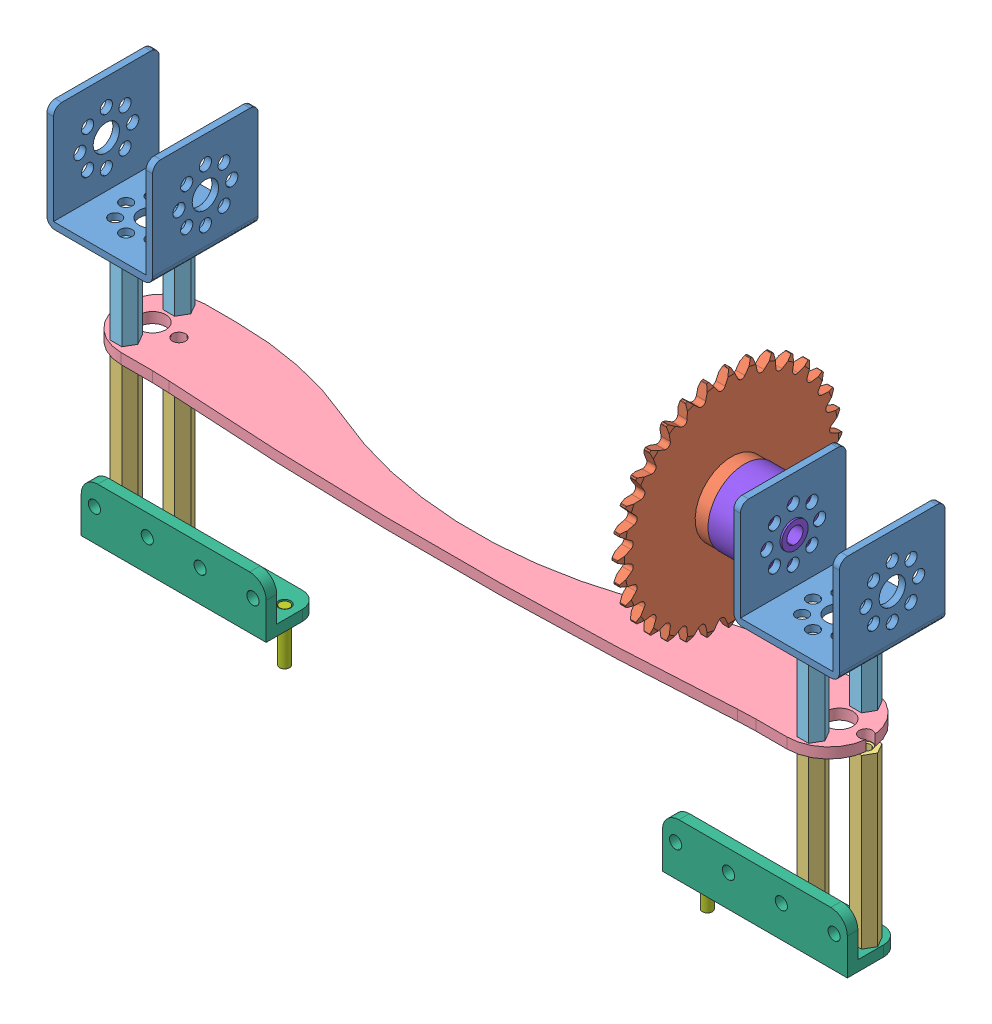
SolidWorks assembly Goal Latch, configuration Default. Lengths in mm.
Overall size (431.8 262.6 648.94).
16 component instances, 8 part files, 45 mates.
Components (placement in the parent):
- Tetrix Channel 32mm-1: Tetrix Channel 32mm [Default] at (-103.35 212.6 177.8) size (32 32 32)
- Tetrix Channel 32mm-2: Tetrix Channel 32mm [Default] at (104.65 212.6 177.8) size (32 32 32)
- Tetrix Sprocket 32T-1: Tetrix Sprocket 32T [Default] at (71.95 228.6 177.8) x (0 1 0) z (1 0 0) size (68 68 6.8)
- Tetrix Standoff 2in'-1: Tetrix Standoff 2in' [Default] at (-111.35 184.025 177.8) x (1 0 0) z (0 -1 0) size (7.16 6.2 50.8)
- Goal Latch Bar (Plasmacut)-1: Goal Latch Bar (Plasmacut) [Default] at (-100.175 187.2 177.8) x (1 0 0) z (0 -1 0) size (226.91 28.57 3.17)
- Tetrix Standoff 1in-1: Tetrix Standoff 1in [Default] at (-103.35 212.6 169.8) x (1 0 0) z (0 -1 0) size (7.16 6.2 25.4)
- Tetrix Standoff 1in-2: Tetrix Standoff 1in [Default] at (-103.35 212.6 185.8) x (1 0 0) z (0 -1 0) size (7.16 6.2 25.4)
- Tetrix Standoff 1in-3: Tetrix Standoff 1in [Default] at (104.65 212.6 169.8) x (1 0 0) z (0 -1 0) size (7.16 6.2 25.4)
- Tetrix Standoff 1in-4: Tetrix Standoff 1in [Default] at (104.65 212.6 185.8) x (1 0 0) z (0 -1 0) size (7.16 6.2 25.4)
- Tetrix Standoff 2in'-2: Tetrix Standoff 2in' [Default] at (-95.35 184.025 177.8) x (1 0 0) z (0 -1 0) size (7.16 6.2 50.8)
- Tetrix Standoff 2in'-3: Tetrix Standoff 2in' [Default] at (112.65 184.025 177.8) x (1 0 0) z (0 -1 0) size (7.16 6.2 50.8)
- Tetrix Standoff 2in'-4: Tetrix Standoff 2in' [Default] at (96.65 184.025 177.8) x (1 0 0) z (0 -1 0) size (7.16 6.2 50.8)
- Goal Latch Angle-1: Goal Latch Angle [Default] at (-39.35 130.025 187.4) x (0 0 -1) z (1 0 0) size (16 16 56)
- Goal Latch Angle-2: Goal Latch Angle [Default] at (136.65 130.025 187.4) x (0 0 -1) z (1 0 0) size (16 16 56)
- Part1^Goal Latch-2: Part1^Goal Latch [Default] at (-39.35 130.025 187.4) x (0 0 1) z (0 -1 0) size (3 131 15.7) (virtual)
- Tetrix Gear Spacer-1: Tetrix Gear Spacer [Default] at (82.3 228.6 177.8) x (0 0 1) z (-1 0 0) size (22.2 22.2 17.75)
Mates (geometry in assembly coordinates):
- Coincident3: coincident aligned: plane of Tetrix Channel 32mm-1 through (-119.35 212.6 161.8) normal (0 -1 0); plane of Tetrix Channel 32mm-2 through (88.65 212.6 161.8) normal (0 -1 0)
- Distance4: distance = 120.65 mm aligned: plane of Tetrix Channel 32mm-2 through (120.65 212.6 161.8) normal (1 0 0); plane of assembly through (0 0 0) normal (1 0 0)
- Concentric23: concentric aligned: cylinder of Tetrix Channel 32mm-1 through (-87.35 228.6 177.8) axis (1 0 0) radius 4; cylinder of Tetrix Channel 32mm-2 through (120.65 228.6 177.8) axis (1 0 0) radius 4
- Concentric24: concentric aligned: cylinder of Tetrix Channel 32mm-2 through (120.65 228.6 177.8) axis (1 0 0) radius 4; cylinder of Tetrix Sprocket 32T-1 through (69.15 228.6 177.8) axis (1 0 0) radius 4
- Distance7: distance = 177.8 mm: plane of assembly through (0 0 0) normal (0 0 1); axis of Tetrix Channel 32mm-1 through (-89.35 228.6 177.8) axis (1 0 0)
- Distance8: distance = 228.6 mm: axis of Tetrix Sprocket 32T-1 through (75.95 228.6 177.8) axis (-1 0 0); plane of assembly
- Concentric25: concentric aligned: cylinder of Tetrix Channel 32mm-2 through (120.65 228.6 185.8) axis (1 0 0) radius 1.85; cylinder of Tetrix Sprocket 32T-1 through (69.15 228.6 185.8) axis (1 0 0) radius 1.8
- Coincident11: coincident aligned: plane of Tetrix Standoff 1in-1 through (-103.35 212.6 169.8) normal (0 1 0); plane of Tetrix Standoff 1in-2 through (-103.35 212.6 185.8) normal (0 1 0)
- Coincident12: coincident aligned: plane of Tetrix Standoff 1in-2 through (-103.35 212.6 185.8) normal (0 1 0); plane of Tetrix Standoff 1in-4 through (104.65 212.6 185.8) normal (0 1 0)
- Coincident13: coincident aligned: plane of Tetrix Standoff 1in-3 through (104.65 212.6 169.8) normal (0 1 0); plane of Tetrix Standoff 1in-4 through (104.65 212.6 185.8) normal (0 1 0)
- Coincident14: coincident anti-aligned: plane of Tetrix Channel 32mm-2 through (88.65 212.6 161.8) normal (0 -1 0); plane of Tetrix Standoff 1in-3 through (104.65 212.6 169.8) normal (0 1 0)
- Concentric26: concentric aligned: cylinder of Tetrix Channel 32mm-2 through (104.65 214.6 185.8) axis (0 1 0) radius 1.85; cylinder of Tetrix Standoff 1in-4 through (104.65 187.2 185.8) axis (0 1 0) radius 1.5
- Concentric27: concentric aligned: cylinder of Tetrix Channel 32mm-2 through (104.65 214.6 169.8) axis (0 1 0) radius 1.85; cylinder of Tetrix Standoff 1in-3 through (104.65 187.2 169.8) axis (0 1 0) radius 1.5
- Concentric28: concentric aligned: cylinder of Tetrix Channel 32mm-1 through (-103.35 214.6 185.8) axis (0 1 0) radius 1.85; cylinder of Tetrix Standoff 1in-2 through (-103.35 187.2 185.8) axis (0 1 0) radius 1.5
- Concentric29: concentric aligned: cylinder of Tetrix Channel 32mm-1 through (-103.35 214.6 169.8) axis (0 1 0) radius 1.85; cylinder of Tetrix Standoff 1in-1 through (-103.35 187.2 169.8) axis (0 1 0) radius 1.5
- Parallel1: parallel aligned: plane of Tetrix Standoff 1in-1 through (-101.5602 212.6 172.9) normal (0 0 1); plane of Tetrix Standoff 1in-2 through (-101.5602 212.6 188.9) normal (0 0 1)
- Parallel2: parallel aligned: plane of Tetrix Channel 32mm-1 through (-103.35 212.6 193.8) normal (0 0 1); plane of Tetrix Standoff 1in-2 through (-101.5602 212.6 188.9) normal (0 0 1)
- Parallel3: parallel aligned: plane of Tetrix Standoff 1in-2 through (-101.5602 212.6 188.9) normal (0 0 1); plane of Tetrix Standoff 1in-4 through (106.4398 212.6 188.9) normal (0 0 1)
- Parallel4: parallel aligned: plane of Tetrix Standoff 1in-3 through (106.4398 212.6 172.9) normal (0 0 1); plane of Tetrix Standoff 1in-4 through (106.4398 212.6 188.9) normal (0 0 1)
- Coincident19: coincident anti-aligned: plane of Goal Latch Bar (Plasmacut)-1 through (-100.175 187.2 177.8) normal (0 1 0); plane of Tetrix Standoff 1in-4 through (104.65 187.2 185.8) normal (0 -1 0)
- Concentric30: concentric anti-aligned: cylinder of Goal Latch Bar (Plasmacut)-1 through (104.65 187.2 185.8) axis (0 -1 0) radius 1.9844; cylinder of Tetrix Standoff 1in-4 through (104.65 187.2 185.8) axis (0 1 0) radius 1.5
- Concentric31: concentric anti-aligned: cylinder of Goal Latch Bar (Plasmacut)-1 through (104.65 187.2 169.8) axis (0 -1 0) radius 1.9844; cylinder of Tetrix Standoff 1in-3 through (104.65 187.2 169.8) axis (0 1 0) radius 1.5
- Concentric33: concentric anti-aligned: cylinder of Goal Latch Bar (Plasmacut)-1 through (-103.35 187.2 185.8) axis (0 -1 0) radius 1.9844; cylinder of Tetrix Standoff 1in-2 through (-103.35 187.2 185.8) axis (0 1 0) radius 1.5
- Parallel6: parallel aligned: plane of Tetrix Channel 32mm-2 through (104.65 212.6 193.8) normal (0 0 1); plane of assembly through (0 0 0) normal (0 0 1)
- Coincident21: coincident aligned: plane of Tetrix Standoff 2in'-1 through (-111.35 184.025 177.8) normal (0 1 0); plane of Tetrix Standoff 2in'-2 through (-95.35 184.025 177.8) normal (0 1 0)
- Coincident22: coincident aligned: plane of Tetrix Standoff 2in'-3 through (112.65 184.025 177.8) normal (0 1 0); plane of Tetrix Standoff 2in'-4 through (96.65 184.025 177.8) normal (0 1 0)
- Coincident23: coincident aligned: plane of Tetrix Standoff 2in'-2 through (-95.35 184.025 177.8) normal (0 1 0); plane of Tetrix Standoff 2in'-4 through (96.65 184.025 177.8) normal (0 1 0)
- Coincident24: coincident anti-aligned: plane of Goal Latch Bar (Plasmacut)-1 through (-100.175 184.025 177.8) normal (0 -1 0); plane of Tetrix Standoff 2in'-2 through (-95.35 184.025 177.8) normal (0 1 0)
- Concentric34: concentric anti-aligned: cylinder of Goal Latch Bar (Plasmacut)-1 through (-95.35 187.2 177.8) axis (0 -1 0) radius 1.9844; cylinder of Tetrix Standoff 2in'-2 through (-95.35 133.225 177.8) axis (0 1 0) radius 1.5
- Concentric35: concentric anti-aligned: cylinder of Tetrix Standoff 2in'-1 through (-111.35 133.225 177.8) axis (0 1 0) radius 1.5; cylinder of Goal Latch Bar (Plasmacut)-1 through (-111.35 187.2 177.8) axis (0 -1 0) radius 1.9844
- Concentric36: concentric anti-aligned: cylinder of Goal Latch Bar (Plasmacut)-1 through (96.65 187.2 177.8) axis (0 -1 0) radius 1.9844; cylinder of Tetrix Standoff 2in'-4 through (96.65 133.225 177.8) axis (0 1 0) radius 1.5
- Concentric37: concentric anti-aligned: cylinder of Goal Latch Bar (Plasmacut)-1 through (112.65 187.2 177.8) axis (0 -1 0) radius 1.9844; cylinder of Tetrix Standoff 2in'-3 through (112.65 133.225 177.8) axis (0 1 0) radius 1.5
- Coincident26: coincident anti-aligned: plane of Tetrix Standoff 2in'-2 through (-95.35 133.225 177.8) normal (0 -1 0); plane of Goal Latch Angle-1 through (-39.35 133.225 171.4) normal (0 1 0)
- Coincident27: coincident aligned: plane of Goal Latch Angle-1 through (-39.35 133.225 171.4) normal (0 1 0); plane of Goal Latch Angle-2 through (136.65 133.225 171.4) normal (0 1 0)
- Concentric38: concentric anti-aligned: cylinder of Tetrix Standoff 2in'-1 through (-111.35 133.225 177.8) axis (0 1 0) radius 1.5; cylinder of Goal Latch Angle-1 through (-111.35 133.225 177.8) axis (0 -1 0) radius 1.85
- Concentric39: concentric anti-aligned: cylinder of Tetrix Standoff 2in'-2 through (-95.35 133.225 177.8) axis (0 1 0) radius 1.5; cylinder of Goal Latch Angle-1 through (-95.35 133.225 177.8) axis (0 -1 0) radius 1.85
- Concentric40: concentric anti-aligned: cylinder of Tetrix Standoff 2in'-3 through (112.65 133.225 177.8) axis (0 1 0) radius 1.5; cylinder of Goal Latch Angle-2 through (112.65 133.225 177.8) axis (0 -1 0) radius 1.85
- Concentric41: concentric anti-aligned: cylinder of Tetrix Standoff 2in'-4 through (96.65 133.225 177.8) axis (0 1 0) radius 1.5; cylinder of Goal Latch Angle-2 through (96.65 133.225 177.8) axis (0 -1 0) radius 1.85
- InPlace1: in place: plane of Goal Latch Angle-1 through (-39.35 130.025 187.4) normal (0 -1 0); plane of ? through (0 130.025 0) normal (0 -1 0); moOrthogonalPlaneRef_w of Goal Latch Angle-1 through (-39.35 130.025 187.4) normal (0 -1 0); unknown of ?; plane of Goal Latch Angle-1 through (-39.35 130.025 187.4) normal (0 -1 0); line of ? through (-55 0 130.025) axis (0 -1 0); plane of Goal Latch Angle-1 through (-39.35 130.025 187.4) normal (0 -1 0); unknown of Part1^Goal Latch-2
- Coincident28: coincident aligned: plane of Goal Latch Angle-1; plane of Part1^Goal Latch-2
- Coincident29: coincident aligned: moOrthogonalPlaneRef_w of Goal Latch Angle-1 through (-39.35 130.025 187.4) normal (-1 0 0); plane of Part1^Goal Latch-2
- Coincident30: coincident anti-aligned: moOrthogonalPlaneRef_w of Goal Latch Angle-1 through (-39.35 130.025 187.4) normal (0 0 -1); plane of Part1^Goal Latch-2
- Coincident31: coincident anti-aligned: plane of Tetrix Sprocket 32T-1 through (75.95 228.6 177.8) normal (1 0 0); plane of Tetrix Gear Spacer-1 through (75.95 228.6 177.8) normal (-1 0 0)
- Coincident32: coincident anti-aligned: plane of Tetrix Channel 32mm-2 through (88.65 244.6 161.8) normal (-1 0 0); plane of Tetrix Gear Spacer-1 through (88.65 228.6 177.8) normal (1 0 0)
- Concentric42: concentric anti-aligned: cylinder of Tetrix Channel 32mm-2 through (120.65 228.6 177.8) axis (1 0 0) radius 4; cylinder of Tetrix Gear Spacer-1 through (75.95 228.6 177.8) axis (-1 0 0) radius 11.1
